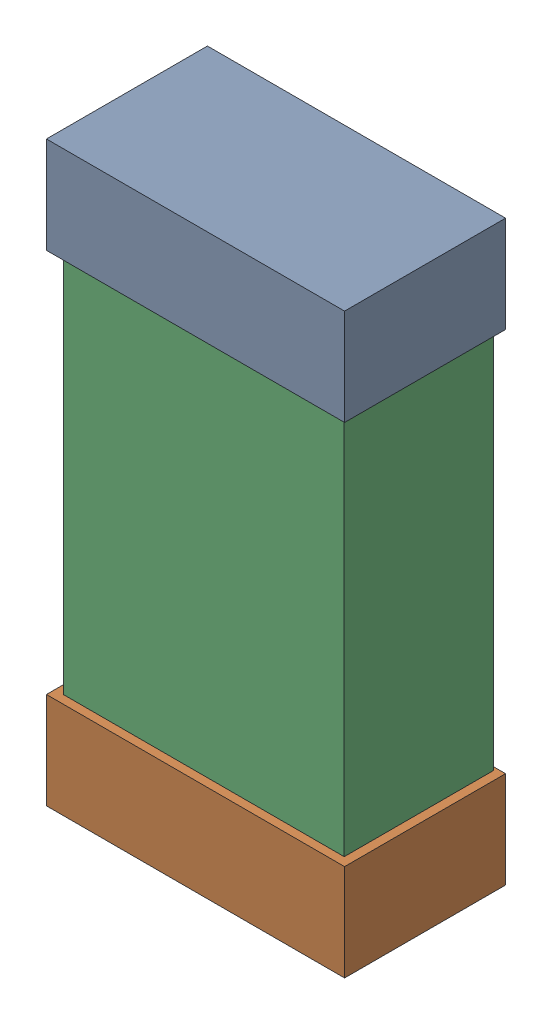
SolidWorks assembly C39, configuration Default. Lengths in mm.
Overall size (0.85 1.65 0.46).
6 component instances, 2 part files, 0 mates.
Components (placement in the parent):
- 432138512_44-1: 432138512_44 [Default] at (15.4501 62.7862 -0.8715) size (0.85 0.28 0.46)
  - Extruded-1: Extruded [Default] at origin size (0.85 0.28 0.46)
- 432138512_45-1: 432138512_45 [Default] at (15.4501 61.4147 -0.8715) size (0.85 0.28 0.46)
  - Extruded-1: Extruded [Default] at origin size (0.85 0.28 0.46)
- 432124816_22-1: 432124816_22 [Default] at (15.4501 62.1005 -0.8615) size (0.8 1.5 0.42)
  - Extruded (1)-1: Extruded (1) [Default] at origin size (0.8 1.5 0.42)
